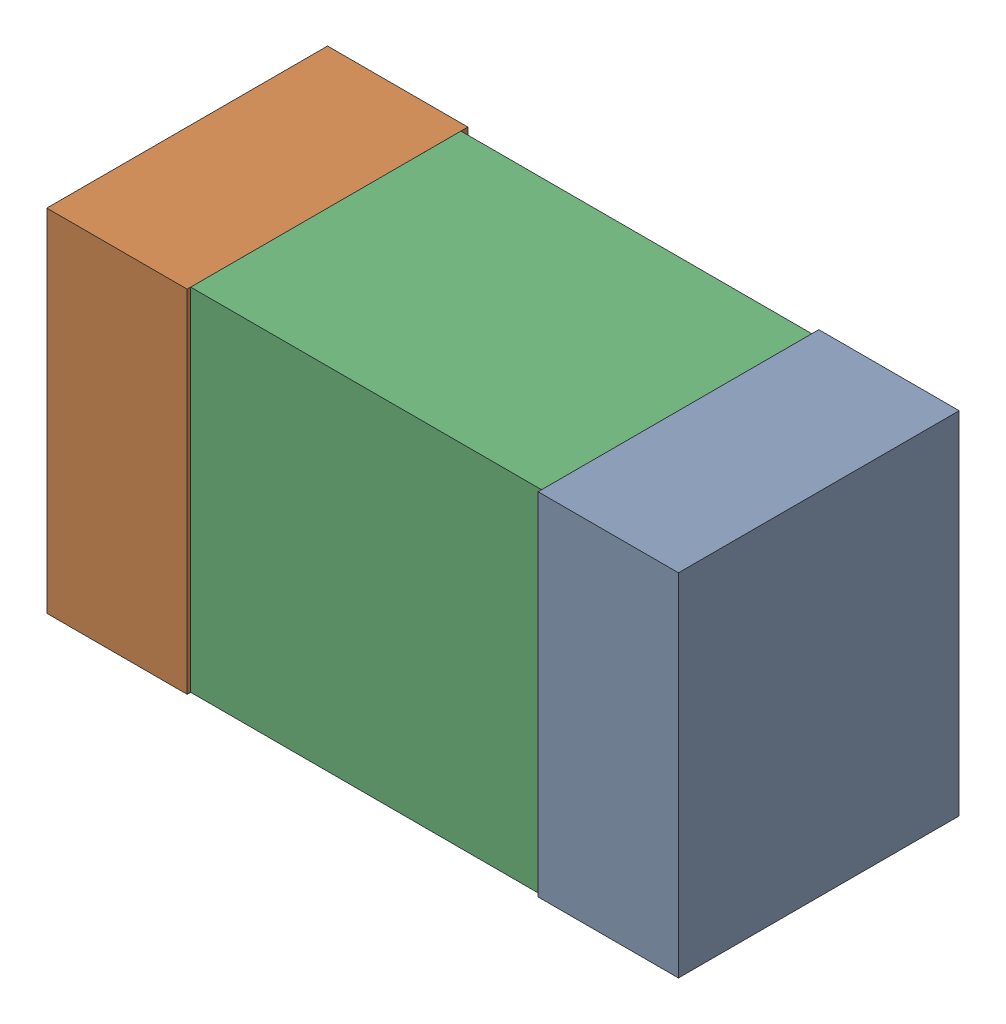
SolidWorks assembly L404PCB, configuration Default. Lengths in mm.
Overall size (1.8 1 0.8).
6 component instances, 2 part files, 0 mates.
Components (placement in the parent):
- 854785840-1: 854785840 [Default] at (117.3001 90.1999 -2.4638) size (0.4 1 0.8)
  - Extruded_4-1: Extruded_4 [Default] at origin size (0.4 1 0.8)
- 854785840-2: 854785840 [Default] at (115.9001 90.1999 -2.4638) size (0.4 1 0.8)
  - Extruded_4-1: Extruded_4 [Default] at origin size (0.4 1 0.8)
- 846483152-1: 846483152 [Default] at (116.6001 90.1999 -2.4438) size (1 1 0.77)
  - Extruded_3-1: Extruded_3 [Default] at origin size (1 1 0.77)
